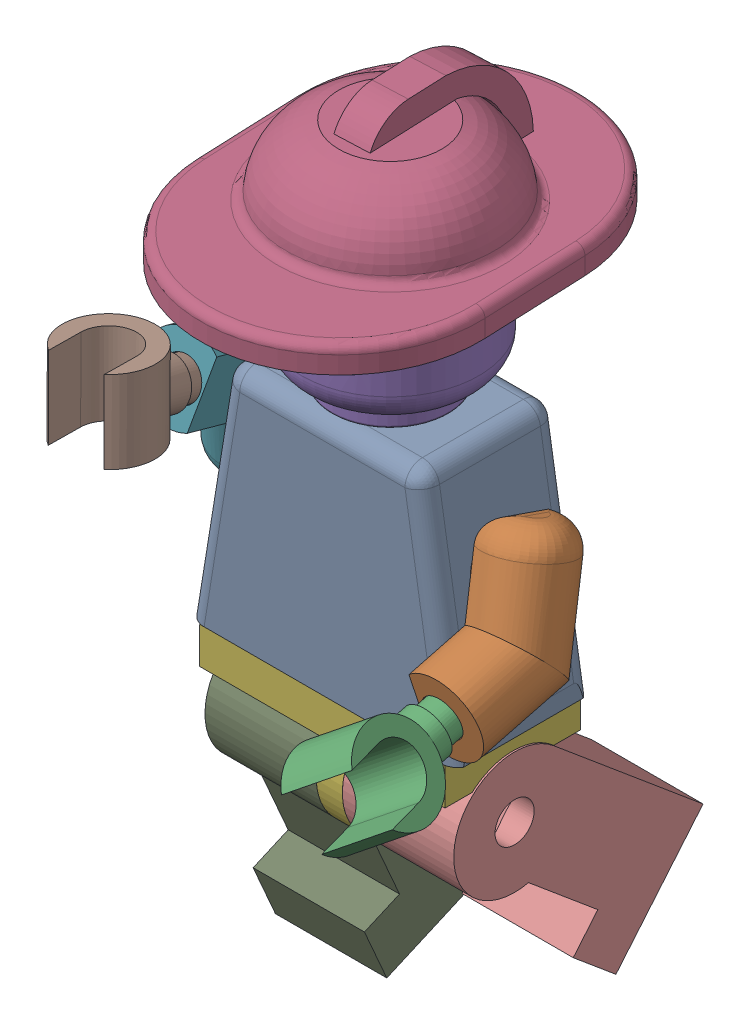
SolidWorks assembly robot assembly, configuration Default. Lengths in mm.
Overall size (23.47 44.88 23.98).
10 component instances, 7 part files, 24 mates.
Components (placement in the parent):
- robot body-1: robot body [Default] at (-3.6384 -3.3068 2.2982) size (15.3 19.2 7.8)
- robot hand-1: robot hand [Default] at (4.8161 -6.2969 7.7535) x (0.98722 0.159364 0) z (0.034121 -0.211373 0.97681) size (6.7 8.08 8.98)
- robot hand1-1: robot hand1 [Default] at (6.5061 -6.0805 11.9659) x (-0.579228 0.792309 0.191682) z (-0.785901 -0.605216 0.126781) size (5 11.08 5.6)
- robot hat-1: robot hat [Default] at (-3.6384 12.5432 2.2982) x (-0.040964 0 -0.999161) z (0.999161 0 -0.040964) size (22 7 16)
- robot head-1: robot head [Default] at (-3.6384 28.5206 2.2982) x (-0.163867 0 -0.986482) z (0.986482 0 -0.163867) size (10.2 11 10.2)
- robot hip joint-1: robot hip joint [Default] at (-3.6384 -14.8568 2.2982) size (14.1 13 7.8)
- robot hand-2: robot hand [Default] at (-10.6474 2.6589 7.3445) x (-0.987223 0.159345 0) z (0.047985 0.297292 0.95358) size (6.7 8.08 8.98)
- robot hand1-2: robot hand1 [Default] at (-10.3003 2.0733 11.8371) x (0.995767 0.06069 -0.069029) z (-0.065591 0.99531 -0.0711) size (5 11.08 5.6)
- robot leg-2: robot leg [Default] at (-7.5884 -14.8568 2.2982) x (0 -0.401051 0.916056) z (-1 0 0) size (7.8 14.7 6.4)
- robot leg-3: robot leg [Default] at (0.3116 -14.8568 2.2982) x (0 -0.766564 0.642168) z (-1 0 0) size (7.8 14.7 6.4)
Mates (geometry in assembly coordinates):
- Concentric3: concentric anti-aligned: cylinder of robot body-1 through (-3.6384 9.0432 2.2982) axis (0 -1 0) radius 2.4; cylinder of robot head-1 through (-3.6384 65.3873 2.2982) axis (0 1 0) radius 5.1
- Coincident1: coincident aligned: plane of robot body-1 through (1.9615 3.5432 6.1982) normal (0 1 0); circle of robot head-1
- Concentric4: concentric anti-aligned: cylinder of robot body-1 through (-12.1729 -4.6845 2.2982) axis (0.98722 0.159364 0) radius 1.9; cylinder of robot hand-1 through (2.1072 -2.3793 2.2982) axis (-0.98722 -0.159364 0) radius 0.85
- Coincident3: coincident anti-aligned: plane of robot body-1 through (4.0116 -9.1568 6.1982) normal (0.98722 0.159364 0); plane of robot hand-1 through (3.6433 -6.8753 5.7494) normal (-0.98722 -0.159364 0)
- Concentric5: concentric anti-aligned: cylinder of robot hand-1 through (4.6626 -5.3457 3.3579) axis (0.034121 -0.211373 0.97681) radius 1.125; cylinder of robot hand1-1 through (4.6626 -5.3457 3.3579) axis (-0.034121 0.211373 -0.97681) radius 1.0898
- Coincident4: coincident anti-aligned: plane of robot hand-1 through (4.6626 -5.3457 3.3579) normal (0.034121 -0.211373 0.97681); plane of robot hand1-1 through (5.5501 -4.722 3.4618) normal (-0.034121 0.211373 -0.97681)
- Concentric7: concentric aligned: cylinder of robot hat-1 through (-3.6384 14.5432 2.2982) axis (0 1 0) radius 2.45; cylinder of robot head-1 through (-3.6384 12.5432 2.2982) axis (0 1 0) radius 1.6
- Coincident6: coincident anti-aligned: plane of robot hat-1 through (-3.6384 14.5432 2.2982) normal (0 -1 0); plane of robot head-1 through (-3.6384 14.5432 2.2982) normal (0 1 0)
- Concentric8: concentric anti-aligned: cylinder of robot body-1 through (4.8961 -4.6843 2.2982) axis (-0.987223 0.159345 0) radius 1.9; cylinder of robot hand-2 through (-9.3841 -2.3794 2.2982) axis (0.987223 -0.159345 0) radius 0.85
- Concentric10: concentric aligned: cylinder of robot body-1 through (4.8961 -4.6843 2.2982) axis (-0.987223 0.159345 0) radius 1.9; cylinder of robot hand-2 through (-8.9892 -2.4432 2.2982) axis (-0.987223 0.159345 0) radius 1.85
- Concentric11: concentric aligned: cylinder of robot body-1 through (4.8961 -4.6843 2.2982) axis (-0.987223 0.159345 0) radius 1.9; cylinder of robot hand-2 through (-8.9892 -2.4432 2.2982) axis (-0.987223 0.159345 0) radius 1.85
- Concentric14: concentric anti-aligned: cylinder of robot hand-2 through (-10.8634 1.3211 3.0534) axis (0.047985 0.297292 0.95358) radius 1.125; cylinder of robot hand1-2 through (-10.8634 1.3211 3.0534) axis (-0.047985 -0.297292 -0.95358) radius 1.0898
- Coincident12: coincident anti-aligned: plane of robot hand-2 through (-10.8634 1.3211 3.0534) normal (0.047985 0.297292 0.95358); plane of robot hand1-2 through (-10.7779 0.2827 3.3728) normal (-0.047985 -0.297292 -0.95358)
- Concentric17: concentric anti-aligned: cylinder of robot body-1 through (4.8961 -4.6843 2.2982) axis (-0.987223 0.159345 0) radius 1.9; cylinder of robot hand-2 through (-9.3841 -2.3794 2.2982) axis (0.987223 -0.159345 0) radius 0.85
- Coincident19: coincident anti-aligned: plane of robot body-1 through (-9.2385 3.5432 6.1982) normal (-0.987223 0.159345 0); plane of robot hand-2 through (-9.3812 2.6594 5.314) normal (0.987223 -0.159345 0)
- Coincident20: coincident aligned: circle of robot body-1; plane of robot hip joint-1 through (3.4116 -10.1568 2.2982) normal (0 1 0)
- Coincident21: coincident aligned: plane of robot body-1 through (-3.6384 -3.3068 6.1982) normal (0 0 1); plane of robot hip joint-1 through (3.4116 -14.8568 6.1982) normal (0 0 1)
- Width1: width anti-aligned: plane of robot body-1 through (-11.2884 -9.1568 6.1982) normal (-1 0 0); plane of robot hip joint-1 through (4.0116 -10.1568 6.1982) normal (1 0 0); plane of robot body-1 through (3.4116 -14.8568 2.2982) normal (1 0 0); plane of robot hip joint-1 through (-10.6884 -14.8568 2.2982) normal (-1 0 0)
- Concentric18: concentric: cylinder of robot hip joint-1 through (0.7116 -14.8568 2.2982) axis (-1 0 0) radius 1; cylinder of robot leg-1 through (10.2817 -14.2011 3.737) axis (0 -0.105706 -0.994397) radius 2.4
- Concentric20: concentric: cylinder of robot hip joint-1 through (0.7116 -14.8568 2.2982) axis (-1 0 0) radius 1; cylinder of robot leg-1 through (7.0817 -14.8568 2.2982) axis (1 0 0) radius 1.125
- Coincident23: coincident anti-aligned: plane of robot hip joint-1 through (-4.3884 -14.8568 2.2982) normal (-1 0 0); plane of robot leg-2 through (-4.3884 -14.8568 2.2982) normal (1 0 0)
- Concentric21: concentric aligned: cylinder of robot hip joint-1 through (-7.9884 -14.8568 2.2982) axis (1 0 0) radius 1; cylinder of robot leg-2 through (-10.7884 -14.8568 2.2982) axis (1 0 0) radius 1.125
- Coincident24: coincident anti-aligned: plane of robot hip joint-1 through (-2.8884 -14.8568 2.2982) normal (1 0 0); plane of robot leg-3 through (-2.8884 -14.8568 2.2982) normal (-1 0 0)
- Concentric22: concentric anti-aligned: cylinder of robot hip joint-1 through (0.7116 -14.8568 2.2982) axis (-1 0 0) radius 1; cylinder of robot leg-3 through (-2.8884 -14.8568 2.2982) axis (1 0 0) radius 1.125
